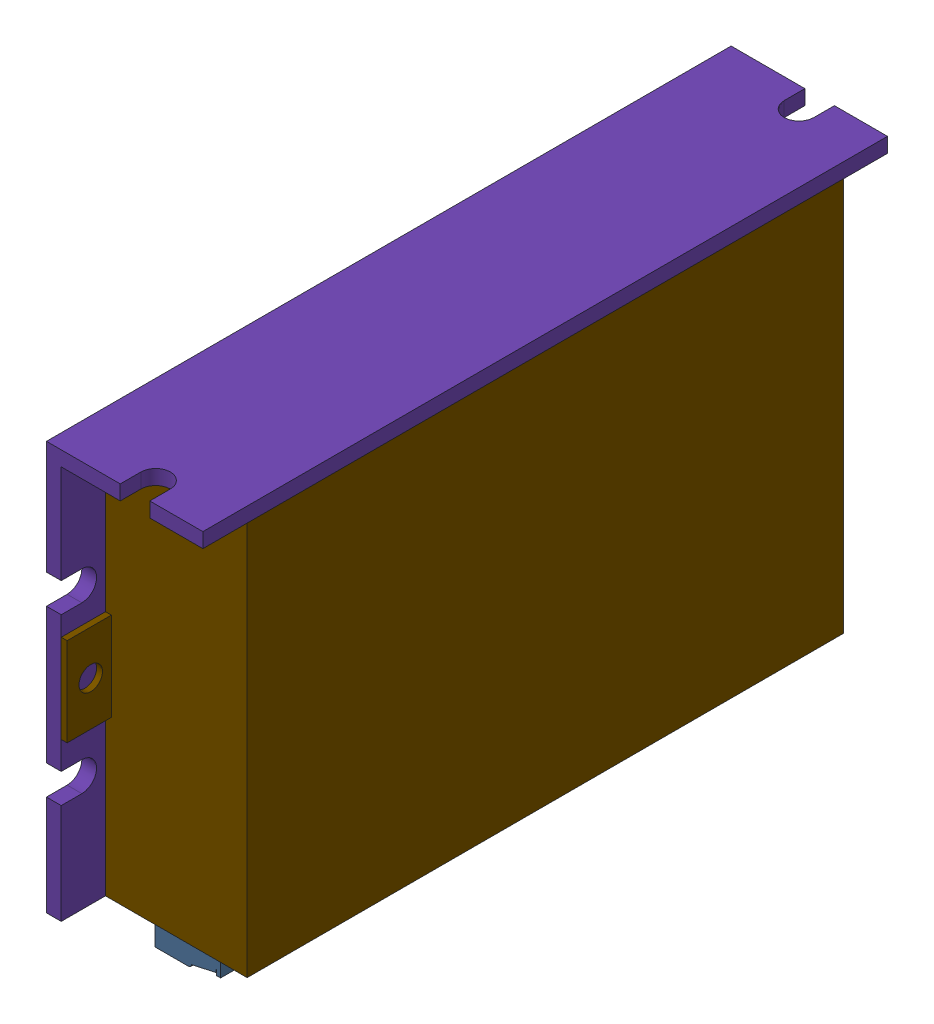
SolidWorks assembly LEADSHINE Stepper Driver CS-D508 v4 for new, configuration Default. Lengths in mm.
Overall size (26.5 78 116).
20 component instances, 18 part files, 0 mates.
Components (placement in the parent):
- Component7-1: Component7 [Component7] at origin size (19.6 67.18 94.5)
  - RJ12 v2-1: RJ12 v2 [RJ12 v2] at origin size (17.7 14.34 13)
    - Fusion011-1: Fusion011 [Fusion011] at (21.75 14.2 -49.5) x (0 -1 0) z (-1 0 0) size (0.6 8.66 11.78)
    - Fusion010-1: Fusion010 [Fusion010] at (21.75 21.4 -49.5) x (0 -1 0) z (-1 0 0) size (0.6 8.66 11.78)
    - Fusion009-1: Fusion009 [Fusion009] at (21.75 19 -49.5) x (0 -1 0) z (-1 0 0) size (0.6 8.66 11.78)
    - Fusion008-1: Fusion008 [Fusion008] at (21.75 19 -49.5) x (0 -1 0) z (-1 0 0) size (0.6 8.66 11.78)
    - Fusion007-1: Fusion007 [Fusion007] at (21.75 16.6 -49.5) x (0 -1 0) z (-1 0 0) size (0.6 8.66 11.78)
    - Fusion006-1: Fusion006 [Fusion006] at (21.75 16.6 -49.5) x (0 -1 0) z (-1 0 0) size (0.6 8.66 11.78)
    - Fusion005-1: Fusion005 [Fusion005] at (21.75 16.6 -49.5) x (0 -1 0) z (-1 0 0) size (14.34 13 17.7)
  - 15EDGK-3.81-04P-14-00AH v1-1: 15EDGK-3.81-04P-14-00AH v1 [15EDGK-3.81-04P-14-00AH v1] at (5.4 -27.8 16.65) x (0 0 1) z (1 0 0) size (16.03 15.6 11.1)
  - 15EDGK-3.81-06P-14-00AH v1-1: 15EDGK-3.81-06P-14-00AH v1 [15EDGK-3.81-06P-14-00AH v1] at (5.4 -27.8 -7.1) x (0 0 1) z (1 0 0) size (23.65 15.6 11.1)
  - 15EDGK-3.81-03P-14-00AH v1-1: 15EDGK-3.81-03P-14-00AH v1 [15EDGK-3.81-03P-14-00AH v1] at (5.4 -27.8 32.78) x (0 0 1) z (1 0 0) size (12.22 15.6 11.1)
  - 15EDGRC-3.81-03P-14-00AH v1-1: 15EDGRC-3.81-03P-14-00AH v1 [15EDGRC-3.81-03P-14-00AH v1] at (8.75 -25.4 32.78) x (0 0 1) z (1 0 0) size (12.22 9.2 10.6)
  - 15EDGRC-3.81-04P-14-00AH v1-1: 15EDGRC-3.81-04P-14-00AH v1 [15EDGRC-3.81-04P-14-00AH v1] at (8.75 -25.4 16.65) x (0 0 1) z (1 0 0) size (16.03 9.2 10.6)
  - 15EDGK-3.81-08P-14-00AH v1-1: 15EDGK-3.81-08P-14-00AH v1 [15EDGK-3.81-08P-14-00AH v1] at (5.4 -27.8 -38.47) x (0 0 1) z (1 0 0) size (31.27 15.6 11.1)
  - 15EDGRC-3.81-08P-14-00AH v1-1: 15EDGRC-3.81-08P-14-00AH v1 [15EDGRC-3.81-08P-14-00AH v1] at (8.75 -25.4 -38.47) x (0 0 1) z (1 0 0) size (31.27 9.2 10.6)
  - 15EDGRC-3.81-06P-14-00AH v1-1: 15EDGRC-3.81-06P-14-00AH v1 [15EDGRC-3.81-06P-14-00AH v1] at (8.75 -25.4 -7.1) x (0 0 1) z (1 0 0) size (23.65 9.2 10.6)
  - DS1040-08RT v1-1: DS1040-08RT v1 [DS1040-08RT v1] at (8.9 -0.51 -42.55) x (0 1 0) z (1 0 0) size (21.78 11.7 11)
- Component5-1: Component5 [Component5] at origin size (26.5 69.2 116)
- cover-1: cover [cover] at origin size (24 66.7 116)
